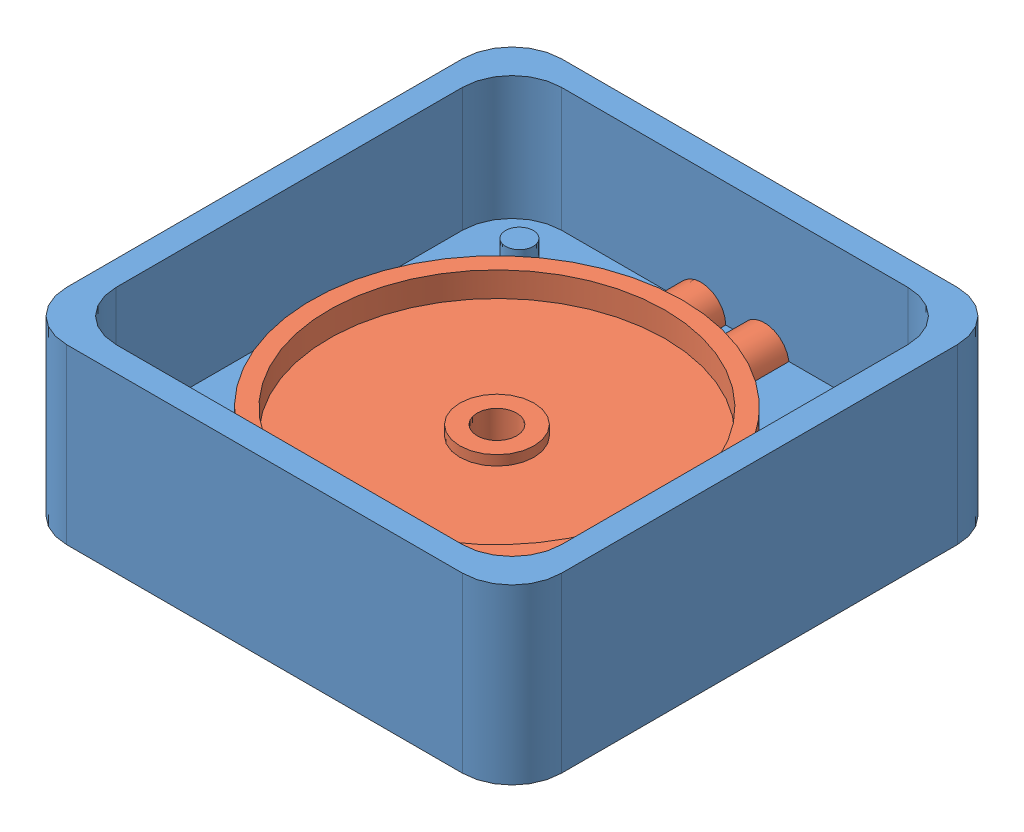
SolidWorks assembly Mold_part_2, configuration Default. Lengths in mm.
Overall size (100 35 100).
2 component instances, 2 part files, 2 mates.
Components (placement in the parent):
- mold_box_1-1: mold_box_1 [Default] at (46.4892 48.6227 69.2491) size (100 35 100)
- Body4-1: Body4 [Default] at (45.9422 68.6227 71.7491) x (-1 0 0) z (0 0 1) size (75 10.3 85)
Mates (geometry in assembly coordinates):
- Coincident1: coincident anti-aligned: plane of mold_box_1-1 through (11.4892 58.6227 34.2491) normal (0 1 0); plane of Body4-1 through (45.9422 58.6227 71.7491) normal (0 -1 0)
- Symmetric1: symmetric aligned: plane of mold_box_1-1 through (11.4892 58.6227 24.2491) normal (0 0 1); plane of Body4-1 through (52.481 57.956 24.2491) normal (0 0 -1); plane of Body4-1 through (39.6634 58.6227 24.2491) normal (0 0 -1)
